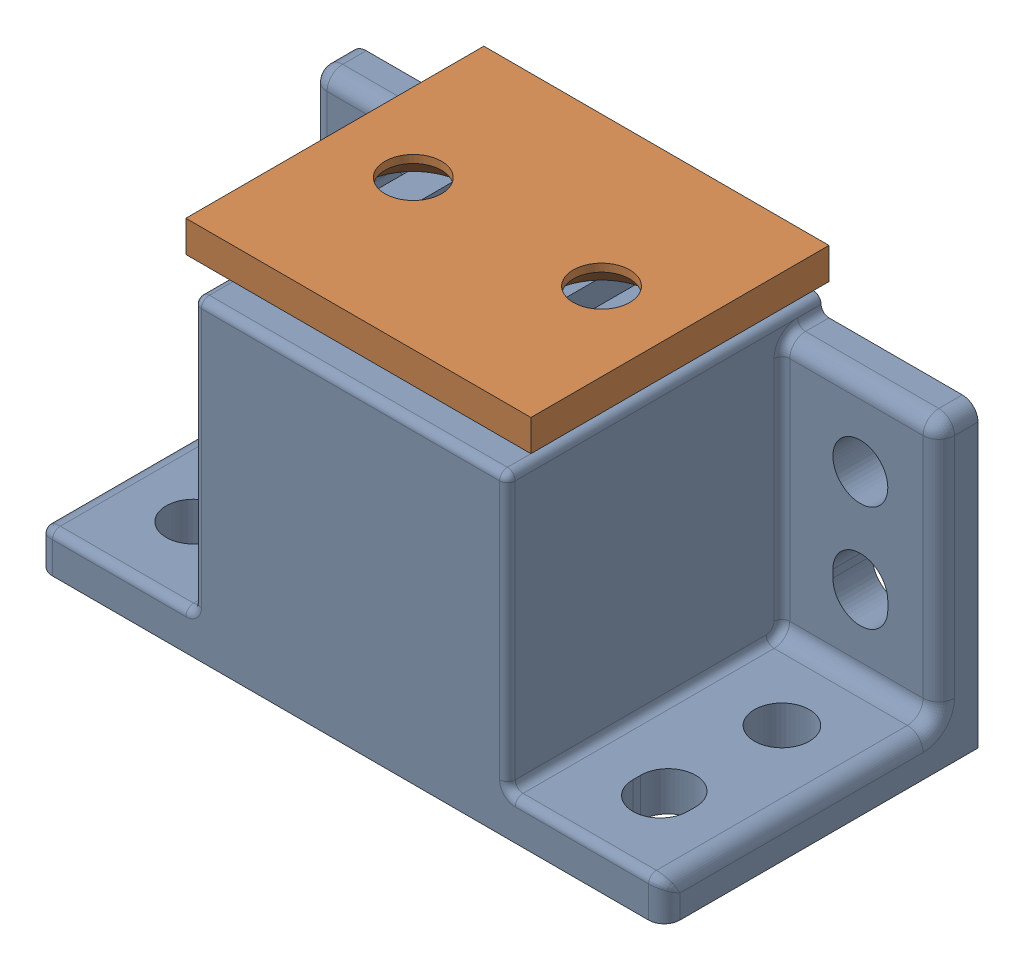
SolidWorks assembly MISUMI_MGCST30, configuration Default. Lengths in mm.
Overall size (40 23.5 20).
2 component instances, 2 part files, 4 mates.
Components (placement in the parent):
- MAGNET_MISUMI_MGCST30-1: MAGNET_MISUMI_MGCST30 [Default] at origin size (40 21.5 20)
- PLATE_MISUMI_MGCST30-1: PLATE_MISUMI_MGCST30 [Default] at (0 23.5 0) x (-1 0 0) z (0 -1 0) size (22 19 2)
Mates (geometry in assembly coordinates):
- Coincident1: coordinate: point of MAGNET_BaseModel20250106202019-1
- Width1: width aligned: plane of PLATE_BaseModel20250106202019-1 through (-11 21.5 -9.5) normal (-1 0 0); plane of PLATE_BaseModel20250106202019-1 through (11 21.5 -9.5) normal (1 0 0); plane of MAGNET_BaseModel20250106202019-1 through (-10 20 10) normal (-1 0 0); plane of MAGNET_BaseModel20250106202019-1 through (10 20 10) normal (1 0 0)
- Width2: width anti-aligned: plane of PLATE_BaseModel20250106202019-1 through (-11 21.5 9.5) normal (0 0 1); plane of MAGNET_BaseModel20250106202019-1 through (-11 21.5 -9.5) normal (0 0 -1); plane of PLATE_BaseModel20250106202019-1 through (0 0 -10) normal (0 0 -1); plane of MAGNET_BaseModel20250106202019-1 through (0 0 10) normal (0 0 1)
- Distance1: distance: plane of PLATE_MISUMI_MGCST30-1 through (0 21.5 0) normal (0 -1 0); plane of MAGNET_MISUMI_MGCST30-1 through (-5 21.5 0) normal (0 1 0)
